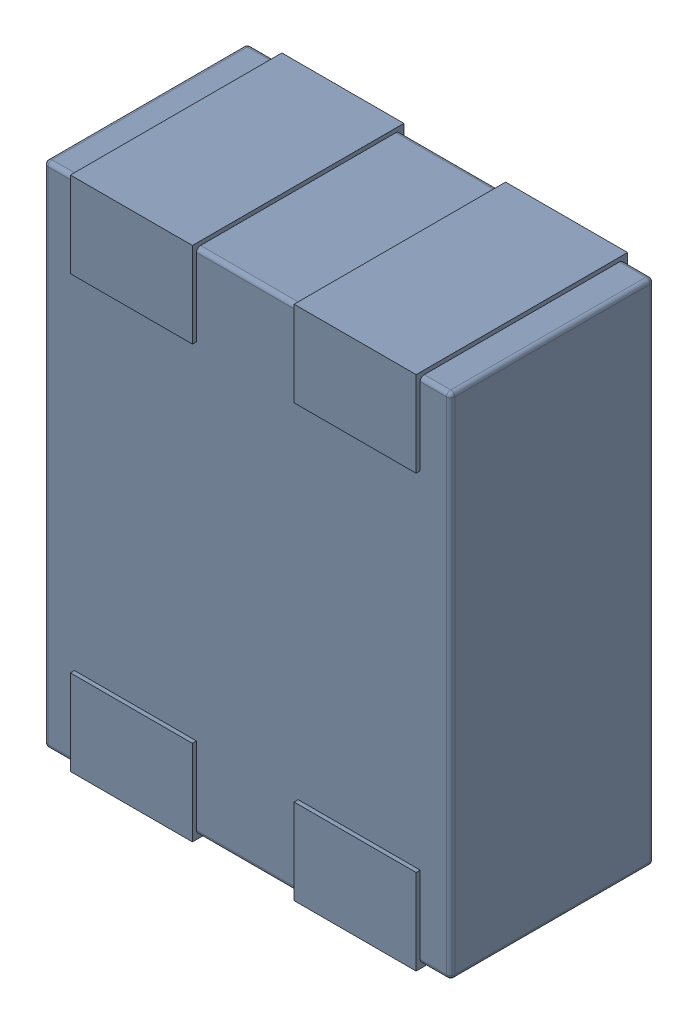
SolidWorks assembly MCZ1210DH900L2TA0G, configuration Défaut. Lengths in mm.
Overall size (1 1.27 0.52).
3 component instances, 1 part files, 0 mates.
Components (placement in the parent):
- 3D_PCB1_2021-12-30 (1).step-1: 3D_PCB1_2021-12-30 (1).step [Défaut] at origin size (1 1.27 0.52)
  - a3ec64f90eb5404ebd79eca0046a794a.step-1: a3ec64f90eb5404ebd79eca0046a794a.step [Défaut] at (5.0419 -6.8961 1.6) size (1 1.27 0.52)
    - SOLID.step_650-1: SOLID.step_650 [Défaut] at origin size (1 1.27 0.52)
